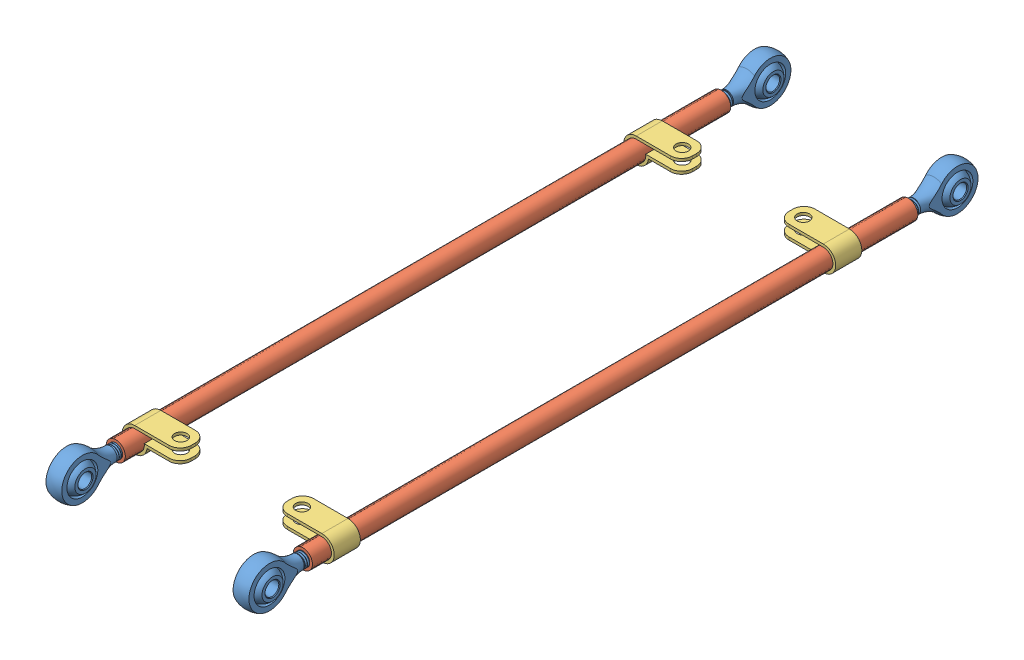
SolidWorks assembly arm-assembly, configuration Default. Lengths in mm.
Overall size (77 16 266).
10 component instances, 3 part files, 17 mates.
Components (placement in the parent):
- rod-end-5mm-11: rod-end-5mm [2988K111] at (-33.9999 0.0005 -112) x (0 1 0) z (-1 0 0) size (16 41.14 8)
- rod-end-5mm-12: rod-end-5mm [2988K111] at (-34 0.0005 112) x (0 1 0) z (1 0 0) size (16 41.14 8)
- carbon-tubes-215-2: carbon-tubes-215 [Default] at (-33.9999 0 0) x (1 0 0) z (0 1 0) size (7 220 7)
- rod-end-5mm-13: rod-end-5mm [2988K111] at (33.9999 -0.0005 -112) x (0 -1 0) z (1 0 0) size (16 41.14 8)
- carbon-tubes-215-3: carbon-tubes-215 [Default] at (33.9999 0 0) x (-1 0 0) z (0 -1 0) size (7 220 7)
- rod-end-5mm-14: rod-end-5mm [2988K111] at (34 -0.0005 112) x (0 -1 0) z (-1 0 0) size (16 41.14 8)
- arm-spring-clip-1: arm-spring-clip [Default] at (33.9999 0 -83.8693) x (1 -0.000008 0) z (0.000008 1 0) size (21 9.5 9)
- arm-spring-clip-2: arm-spring-clip [Default] at (33.9999 0 98.3535) x (1 -0.000008 0) z (0.000008 1 0) size (21 9.5 9)
- arm-spring-clip-3: arm-spring-clip [Default] at (-34 0.0005 -83.8693) x (-1 0.000008 0) z (0.000008 1 0) size (21 9.5 9)
- arm-spring-clip-4: arm-spring-clip [Default] at (-34 0.0005 98.3535) x (-1 0.000008 0) z (0.000008 1 0) size (21 9.5 9)
Mates (geometry in assembly coordinates):
- Concentric10: concentric anti-aligned: cylinder of rod-end-5mm-11 through (-29.9999 0.0005 -133) axis (0 0 -1) radius 2.5; cylinder of carbon-tubes-215-2 through (-30 0 -110) axis (0 0 1) radius 2.5
- Concentric11: concentric aligned: cylinder of rod-end-5mm-12 through (-30.0001 0.0005 133) axis (0 0 1) radius 2.5; cylinder of carbon-tubes-215-2 through (-30 0 -110) axis (0 0 1) radius 2.5
- Coincident11: coincident aligned: plane of carbon-tubes-215-2 through (-30 0 0) normal (0 1 0); plane of assembly through (0 0 0) normal (0 1 0)
- Coincident13: coincident anti-aligned: plane of carbon-tubes-215-2 through (-30 0 0) normal (0 0 -1); plane of assembly through (0 0 0) normal (0 0 1)
- Parallel1: parallel aligned: plane of rod-end-5mm-12 through (-27.1251 -7.9995 133) normal (1 0 0); plane of assembly through (0 0 0) normal (1 0 0)
- Parallel2: parallel aligned: plane of rod-end-5mm-11 through (-27.1249 -7.9995 -133) normal (1 0 0); plane of assembly through (0 0 0) normal (1 0 0)
- Symmetric2: symmetric aligned: plane of rod-end-5mm-11 through (-29.9999 0.0005 -92) normal (0 0 1); plane of rod-end-5mm-12 through (-30.0001 0.0005 92) normal (0 0 -1); plane of assembly through (0 0 0) normal (0 0 1)
- Distance6: distance = 250 mm: axis of rod-end-5mm-12 through (-37.75 0.0005 125) axis (1 0 0); axis of rod-end-5mm-11 through (-30.2499 0.0005 -125) axis (-1 0 0)
- Concentric12: concentric aligned: cylinder of carbon-tubes-215-3 through (30 0 -110) axis (0 0 1) radius 3.5; cylinder of arm-spring-clip-1 through (30 0 -88.6193) axis (0 0 1) radius 3.5
- Concentric13: concentric anti-aligned: cylinder of carbon-tubes-215-2 through (-30 0 -110) axis (0 0 1) radius 3.5; cylinder of arm-spring-clip-3 through (-29.9999 0.0005 -79.1193) axis (0 0 -1) radius 3.5
- Coincident14: coincident aligned: plane of arm-spring-clip-1 through (13.5 4.5001 -88.6193) normal (0.000009 1 0); plane of arm-spring-clip-3 through (-13.4999 4.5004 -79.1193) normal (0.000009 1 0)
- Concentric14: concentric anti-aligned: cylinder of carbon-tubes-215-2 through (-30 0 -110) axis (0 0 1) radius 3.5; cylinder of arm-spring-clip-4 through (-29.9999 0.0005 103.1035) axis (0 0 -1) radius 3.5
- Concentric15: concentric aligned: cylinder of carbon-tubes-215-3 through (30 0 -110) axis (0 0 1) radius 3.5; cylinder of arm-spring-clip-2 through (30 0 93.6035) axis (0 0 1) radius 3.5
- Coincident15: coincident aligned: plane of arm-spring-clip-2 through (13.5 4.5001 93.6035) normal (0.000009 1 0); plane of arm-spring-clip-4 through (-13.4999 4.5004 103.1035) normal (0.000009 1 0)
- Coincident16: coincident aligned: plane of arm-spring-clip-1 through (30 0 -88.6193) normal (0 0 -1); plane of arm-spring-clip-3 through (-29.9999 0.0005 -88.6193) normal (0 0 -1)
- Coincident17: coincident aligned: plane of arm-spring-clip-2 through (30 0 93.6035) normal (0 0 -1); plane of arm-spring-clip-4 through (-29.9999 0.0005 93.6035) normal (0 0 -1)
- Distance7: distance = 30 mm aligned: plane of assembly; plane of rod-end-5mm-12 through (-30 -7.9995 133) normal (1 0 0)
